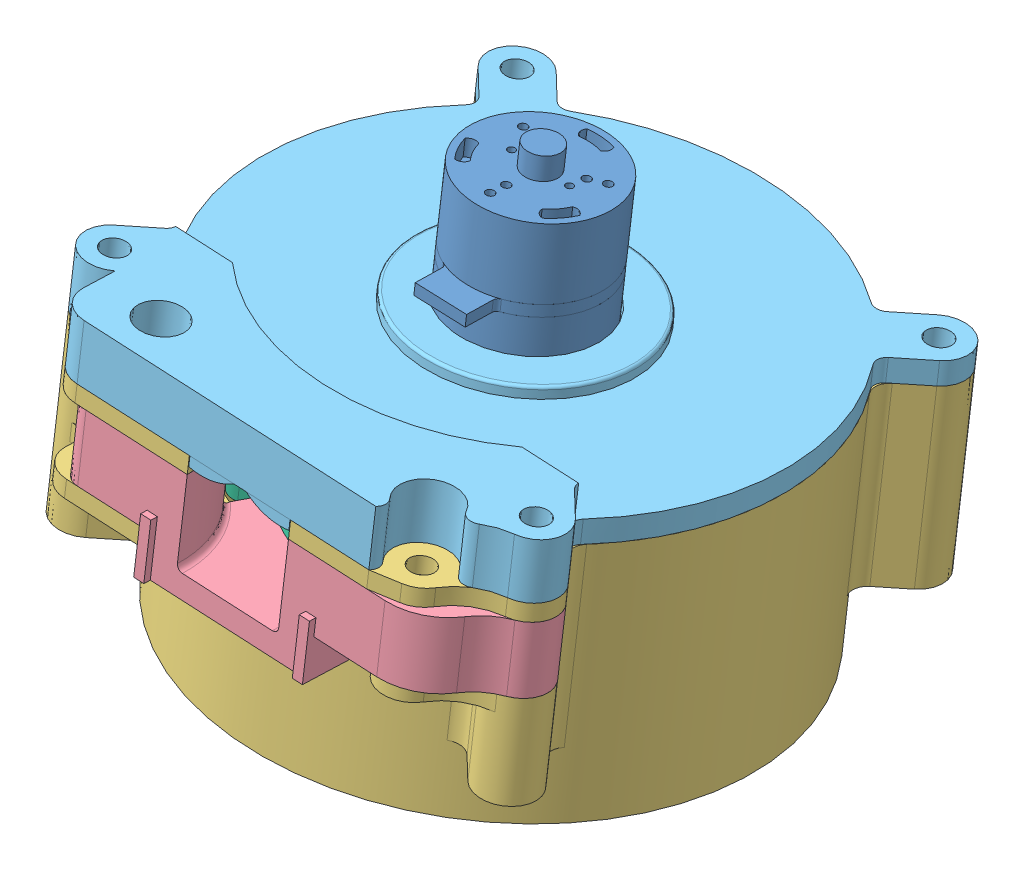
SolidWorks assembly 拨弹模组，上工, configuration 默认. Lengths in mm.
Overall size (100.35 85.69 103.21).
6 component instances, 6 part files, 12 mates.
Components (placement in the parent):
- 新版2006电机(步兵下供弹)IV1.1V1.3-1: 新版2006电机(步兵下供弹)IV1.1V1.3 [默认] at (145.8797 -117.4219 -221.6853) x (-0.123718 -0.957202 0.261647) z (0.055234 0.256621 0.964933) size (64.49 27.18 34.91)
- 轴承30-37-4（步兵下供弹V1.0）IV1.1V1.3-1: 轴承30-37-4（步兵下供弹V1.0）IV1.1V1.3 [默认] at (173.2641 -21.8911 -139.2336) x (0.85725 -0.088252 -0.507281) z (-0.06794 -0.995975 0.058459) size (37 37 4)
- 3D打印-步兵下供弹-弹舱壁上V1.0IV1.1V1.3-1: 3D打印-步兵下供弹-弹舱壁上V1.0IV1.1V1.3 [默认] at (173.8085 -38.0831 -38.132) x (-0.997481 0.069007 0.016423) z (0.06794 0.995975 -0.058459) size (90 96.96 44)
- 3D打印-步兵下供弹-出弹口V1.0IV1.1V1.3-1: 3D打印-步兵下供弹-出弹口V1.0IV1.1V1.3 [默认] at (172.8225 -28.365 -138.8536) x (-0.997481 0.069007 0.016423) z (0.020391 0.057196 0.998155) size (72.5 20.06 33.47)
- 3D打印-步兵下供弹-2006电机套V1.0IV1.1V1.3-2: 3D打印-步兵下供弹-2006电机套V1.0IV1.1V1.3 [默认] at (171.9732 -40.8147 -138.1229) x (0.997481 -0.069007 -0.016423) z (0.020391 0.057195 0.998155) size (90 30 96.96)
- 哨兵拨轮IV1.1V1.3-1: 哨兵拨轮IV1.1V1.3 [默认] at (173.1961 -22.8871 -139.1752) x (-0.53911 -0.012654 -0.84214) z (-0.06794 -0.995975 0.058459) size (70.94 70.91 38)
Mates (geometry in assembly coordinates):
- 重合38: coincident anti-aligned: plane of 3D打印-步兵下供弹-弹舱壁上V1.0IV1.1V1.3-1 through (174.352 -30.1152 -38.5997) normal (0.06794 0.995975 -0.058459); plane of 3D打印-步兵下供弹-出弹口V1.0IV1.1V1.3-1 through (172.3129 -35.8348 -138.4152) normal (-0.06794 -0.995975 0.058459)
- 同心42: concentric aligned: cylinder of 3D打印-步兵下供弹-弹舱壁上V1.0IV1.1V1.3-1 through (199.6991 -35.0377 -93.0075) axis (-0.06794 -0.995975 0.058459) radius 2.15; cylinder of 3D打印-步兵下供弹-出弹口V1.0IV1.1V1.3-1 through (201.2618 -12.1303 -94.352) axis (-0.06794 -0.995975 0.058459) radius 2.05
- 同心43: concentric aligned: cylinder of 3D打印-步兵下供弹-弹舱壁上V1.0IV1.1V1.3-1 through (150.2672 -31.7332 -94.1571) axis (-0.06794 -0.995975 0.058459) radius 2.15; cylinder of 3D打印-步兵下供弹-出弹口V1.0IV1.1V1.3-1 through (151.4902 -13.8057 -95.2093) axis (-0.06794 -0.995975 0.058459) radius 2.05
- 重合42: coincident anti-aligned: plane of 3D打印-步兵下供弹-弹舱壁上V1.0IV1.1V1.3-1 through (187.1668 -18.7941 -87.4165) normal (0.06794 0.995975 -0.058459); plane of 3D打印-步兵下供弹-2006电机套V1.0IV1.1V1.3-2 through (173.332 -20.8952 -139.2921) normal (-0.06794 -0.995975 0.058459)
- 同心47: concentric anti-aligned: cylinder of 3D打印-步兵下供弹-弹舱壁上V1.0IV1.1V1.3-1 through (171.4297 -48.7825 -137.6552) axis (0.06794 0.995975 -0.058459) radius 39; cylinder of 3D打印-步兵下供弹-2006电机套V1.0IV1.1V1.3-2 through (173.332 -20.8952 -139.2921) axis (-0.06794 -0.995975 0.058459) radius 12.5
- 同心48: concentric anti-aligned: cylinder of 3D打印-步兵下供弹-弹舱壁上V1.0IV1.1V1.3-1 through (211.5022 -21.3381 -102.4771) axis (-0.06794 -0.995975 0.058459) radius 2.2; cylinder of 3D打印-步兵下供弹-2006电机套V1.0IV1.1V1.3-2 through (210.1174 -41.6388 -101.2856) axis (0.06794 0.995975 -0.058459) radius 2.2
- 同心49: concentric aligned: cylinder of 新版2006电机(步兵下供弹)IV1.1V1.3-1 through (171.022 -54.7583 -137.3045) axis (-0.06794 -0.995975 0.058459) radius 12.2; cylinder of 3D打印-步兵下供弹-2006电机套V1.0IV1.1V1.3-2 through (173.332 -20.8952 -139.2921) axis (-0.06794 -0.995975 0.058459) radius 12.5
- 重合43: coincident anti-aligned: plane of 新版2006电机(步兵下供弹)IV1.1V1.3-1 through (165.5999 -37.9811 -148.5724) normal (-0.06794 -0.995975 0.058459); plane of 3D打印-步兵下供弹-2006电机套V1.0IV1.1V1.3-2 through (172.177 -37.8267 -138.2983) normal (0.06794 0.995975 -0.058459)
- 同心50: concentric anti-aligned: cylinder of 轴承30-37-4（步兵下供弹V1.0）IV1.1V1.3-1 through (172.9923 -25.875 -138.9998) axis (0.06794 0.995975 -0.058459) radius 15; cylinder of 3D打印-步兵下供弹-2006电机套V1.0IV1.1V1.3-2 through (173.332 -20.8952 -139.2921) axis (-0.06794 -0.995975 0.058459) radius 15
- 重合48: coincident anti-aligned: plane of 轴承30-37-4（步兵下供弹V1.0）IV1.1V1.3-1 through (173.2641 -21.8911 -139.2336) normal (0.06794 0.995975 -0.058459); plane of 3D打印-步兵下供弹-2006电机套V1.0IV1.1V1.3-2 through (173.2641 -21.8911 -139.2336) normal (-0.06794 -0.995975 0.058459)
- 同心51: concentric aligned: cylinder of 新版2006电机(步兵下供弹)IV1.1V1.3-1 through (164.0781 -44.996 -133.0059) axis (0.83949 -0.088731 -0.536081) radius 1.5; cylinder of 哨兵拨轮IV1.1V1.3-1 through (180.0284 -46.6819 -143.1914) axis (0.83949 -0.088731 -0.536081) radius 3
- 同心53: concentric aligned: cylinder of 新版2006电机(步兵下供弹)IV1.1V1.3-1 through (171.022 -54.7583 -137.3045) axis (-0.06794 -0.995975 0.058459) radius 1.25; cylinder of 哨兵拨轮IV1.1V1.3-1 through (173.1961 -22.8871 -139.1752) axis (-0.06794 -0.995975 0.058459) radius 1.5
